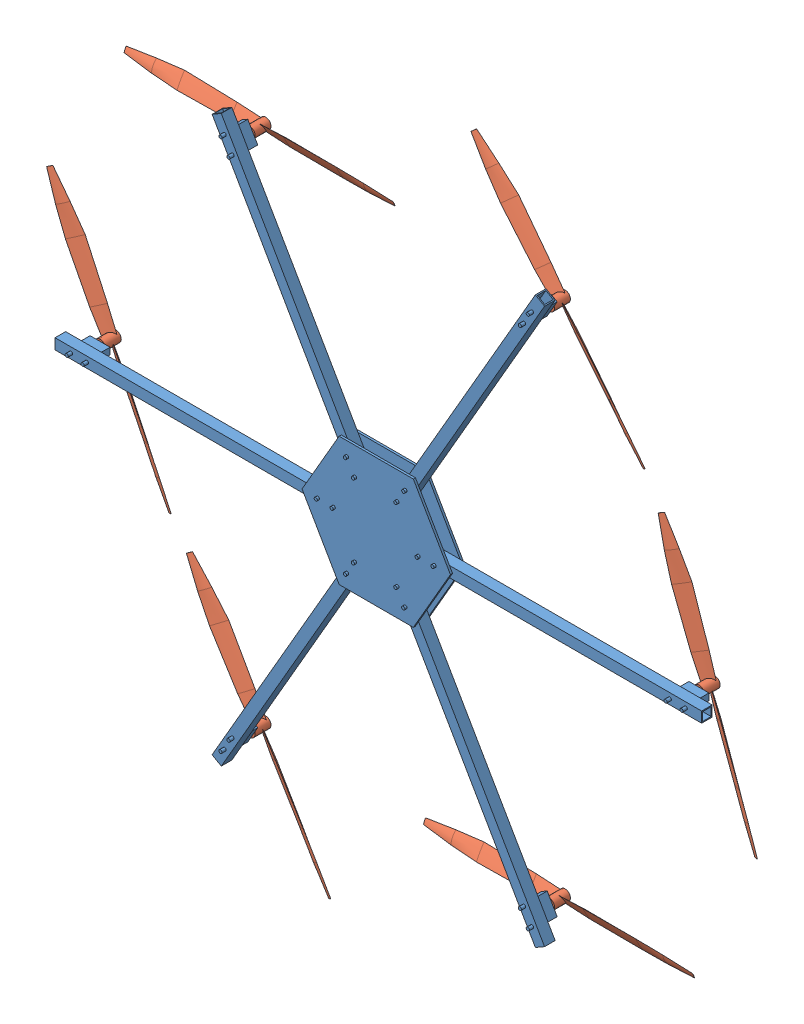
SolidWorks assembly carbonframecomplete, configuration Default. Lengths in mm.
Overall size (678.39 704.11 39).
7 component instances, 2 part files, 6 mates.
Components (placement in the parent):
- carbonframepart-1: carbonframepart [Default] at (142.1541 245.8265 382.5742) size (610.11 533.37 39)
- 10inchprop-1: 10inchprop [Default] at (333.7362 565.2414 465.9576) x (-0.631852 0.775089 0) z (0 0 1) size (254.01 13.44 15)
- 10inchprop-2: 10inchprop [Default] at (475.0126 320.5435 465.9576) x (0.349945 -0.93677 0) z (0 0 1) size (254.01 13.44 15)
- 10inchprop-3: 10inchprop [Default] at (333.7362 75.8456 465.9576) size (254.01 13.44 15)
- 10inchprop-4: 10inchprop [Default] at (51.1833 75.8456 465.9576) x (0.519241 -0.854628 0) z (0 0 1) size (254.01 13.44 15)
- 10inchprop-5: 10inchprop [Default] at (-90.0931 320.5435 465.9576) x (0.44509 -0.895486 0) z (0 0 1) size (254.01 13.44 15)
- 10inchprop-6: 10inchprop [Default] at (51.1833 565.2414 465.9576) size (254.01 13.44 15)
Mates (geometry in assembly coordinates):
- Coincident1: coincident aligned: circle of carbonframepart-1; circle of 10inchprop-1
- Coincident2: coincident aligned: circle of carbonframepart-1; circle of 10inchprop-2
- Coincident3: coincident aligned: circle of carbonframepart-1; circle of 10inchprop-3
- Coincident4: coincident aligned: circle of carbonframepart-1; circle of 10inchprop-4
- Coincident5: coincident aligned: circle of carbonframepart-1; circle of 10inchprop-5
- Coincident6: coincident aligned: circle of carbonframepart-1; circle of 10inchprop-6
